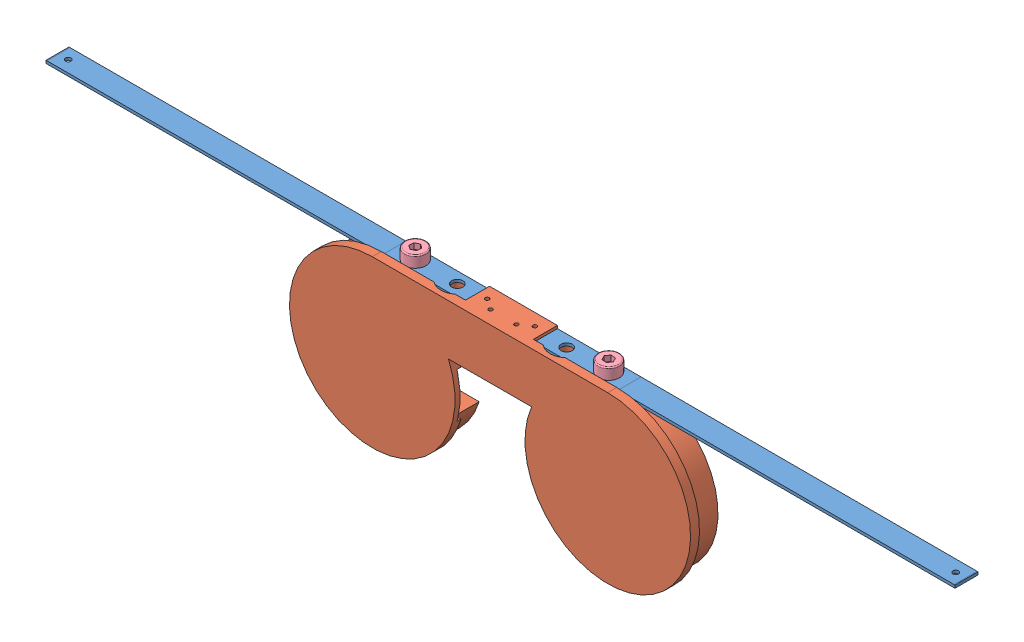
SolidWorks assembly dedede, configuration Valor predeterminado. Lengths in mm.
Overall size (162.11 31.03 6.53).
11 component instances, 4 part files, 31 mates.
Components (placement in the parent):
- antena_01-1: antena_01 [da] at origin size (75 0.58 4.1)
- base deploy^dedede-1: base deploy^dedede [Valor predeterminado] at (-0.0901 0.0537 3.449) x (1 0.000002 0) z (0 0 1) size (71.53 29.53 5.9) (virtual)
- antena_01-3: antena_01 [da] at (-176.7223 -0.0003 10.598) x (-1 -0.000004 0) z (0 0 -1) size (75 0.58 4.1)
- hex thin nut chamfered gradeab_din-5: hex thin nut chamfered gradeab_din [Hexagon Thin Nut ISO 4035 - M2 - N] at (-71.0809 -2.7192 5.3304) x (1 0.000002 0) z (-0.000002 1 0) size (4 4.62 1.2)
- hex thin nut chamfered gradeab_din-6: hex thin nut chamfered gradeab_din [Hexagon Thin Nut ISO 4035 - M2 - N] at (-78.5809 -2.7192 5.3304) x (1 0.000002 0) z (-0.000002 1 0) size (4 4.62 1.2)
- hex thin nut chamfered gradeab_din-7: hex thin nut chamfered gradeab_din [Hexagon Thin Nut ISO 4035 - M2 - N] at (-98.1414 -2.7192 5.2676) x (1 0.000002 0) z (-0.000002 1 0) size (4 4.62 1.2)
- hex thin nut chamfered gradeab_din-8: hex thin nut chamfered gradeab_din [Hexagon Thin Nut ISO 4035 - M2 - N] at (-105.6414 -2.7192 5.2676) x (1 0.000002 0) z (-0.000002 1 0) size (4 4.62 1.2)
- socket head cap screw 4762_din-2: socket head cap screw 4762_din [EN ISO 4762 M2 x 6 - 6N] at (-71.0809 2.5 5.3304) x (0.000002 -1 0) z (-0.074317 0 0.997235) size (8 3.8 3.8)
- socket head cap screw 4762_din-4: socket head cap screw 4762_din [EN ISO 4762 M2 x 6 - 6N] at (-105.6414 2.4999 5.2676) x (0.000002 -1 0) z (-0.570733 -0.000001 0.821136) size (8 3.8 3.8)
- hex thin nut chamfered gradeab_din-9: hex thin nut chamfered gradeab_din [Hexagon Thin Nut ISO 4035 - M5 - N] at (-109.4341 -13.763 7.149) x (0.866026 -0.499998 0) z (0 0 1) size (8 9.24 2.7)
- hex thin nut chamfered gradeab_din-10: hex thin nut chamfered gradeab_din [Hexagon Thin Nut ISO 4035 - M5 - N] at (-67.4341 -13.7629 7.149) x (0.866026 -0.499998 0) z (0 0 1) size (8 9.24 2.7)
Mates (geometry in assembly coordinates):
- Coincidente4: coincident aligned: plane of antena_01-1 through (0 0 0) normal (0 0 1)
- Coincidente5: coincident aligned: plane of antena_01-1 through (0 0 0) normal (0 1 0)
- Coincidente6: coincident aligned: plane of antena_01-1 through (0 0 0) normal (1 0 0)
- Coincidente13: coincident anti-aligned: plane of Peça6^dedede-1 through (-0.0901 0.0001 3.249) normal (-0.000002 1 0); plane of antena_01-3 through (-176.7223 -0.0002 10.598) normal (0.000002 -1 0)
- Coincidente14: coincident aligned: plane of base deploy^dedede-1 through (-0.0901 0.0537 3.249) normal (0 0 -1); plane of antena_01-3 through (-94.4139 0.5783 3.249) normal (0 0 -1)
- Coincidente15: coincident aligned: plane of antena_01-1 through (-7.3085 0.4475 3.249) normal (0 0 -1); plane of base deploy^dedede-1 through (-0.0901 0.0537 3.249) normal (0 0 -1)
- Coincidente16: coincident anti-aligned: plane of antena_01-1 through (0 0.0001 0) normal (0.000002 -1 0); plane of Peça6^dedede-1 through (-0.0901 0.0001 3.249) normal (-0.000002 1 0)
- Coincidente27: coincident anti-aligned: plane of antena_01-1 through (-82.3089 0.5 3.249) normal (-1 -0.000002 0); plane of base deploy^dedede-1 through (-82.3089 1 8.449) normal (1 0.000002 0)
- Coincidente28: coincident anti-aligned: plane of base deploy^dedede-1 through (-94.4134 1 3.249) normal (-1 -0.000002 0); plane of antena_01-3 through (-94.4134 0.5 7.349) normal (1 0.000002 0)
- Coincidente37: coincident anti-aligned: plane of base deploy^dedede-1 through (-69.0809 -4.3191 8.949) normal (-1 -0.000002 0); plane of hex thin nut chamfered gradeab_din-5 through (-69.0809 -3.9191 4.1757) normal (1 0.000002 0)
- Coincidente39: coincident anti-aligned: plane of base deploy^dedede-1 through (-69.0809 -2.7191 8.949) normal (0.000002 -1 0); plane of hex thin nut chamfered gradeab_din-5 through (-71.0809 -2.7192 3.021) normal (-0.000002 1 0)
- Coincidente40: coincident anti-aligned: plane of base deploy^dedede-1 through (-76.5814 -4.3192 8.949) normal (-1 -0.000002 0); plane of hex thin nut chamfered gradeab_din-6 through (-76.5809 -3.9192 4.1757) normal (1 0.000002 0)
- Coincidente41: coincident anti-aligned: plane of base deploy^dedede-1 through (-80.5814 -2.7192 8.949) normal (0.000002 -1 0); plane of hex thin nut chamfered gradeab_din-6 through (-78.5809 -2.7192 3.021) normal (-0.000002 1 0)
- Concêntrico12: concentric anti-aligned: circle of base deploy^dedede-1; circle of hex thin nut chamfered gradeab_din-6
- Coincidente42: coincident anti-aligned: plane of base deploy^dedede-1 through (-100.1408 -2.7192 8.949) normal (0.000002 -1 0); plane of hex thin nut chamfered gradeab_din-7 through (-98.1414 -2.7192 2.9582) normal (-0.000002 1 0)
- Coincidente43: coincident anti-aligned: plane of base deploy^dedede-1 through (-96.1408 -4.3192 8.949) normal (-1 -0.000002 0); plane of hex thin nut chamfered gradeab_din-7 through (-96.1414 -3.9192 4.1129) normal (1 0.000002 0)
- Concêntrico13: concentric anti-aligned: circle of base deploy^dedede-1; circle of hex thin nut chamfered gradeab_din-7
- Coincidente44: coincident anti-aligned: plane of base deploy^dedede-1 through (-107.6414 -2.7192 8.949) normal (0.000002 -1 0); plane of hex thin nut chamfered gradeab_din-8 through (-105.6414 -2.7192 2.9582) normal (-0.000002 1 0)
- Coincidente45: coincident anti-aligned: plane of base deploy^dedede-1 through (-103.6414 -4.3192 8.949) normal (-1 -0.000002 0); plane of hex thin nut chamfered gradeab_din-8 through (-103.6414 -3.9192 4.1129) normal (1 0.000002 0)
- Concêntrico19: concentric aligned: cylinder of base deploy^dedede-1 through (-71.0809 -6 5.3304) axis (-0.000002 1 0) radius 1; cylinder of socket head cap screw 4762_din-2 through (-71.0809 34.25 5.3304) axis (-0.000002 1 0) radius 1.9
- Concêntrico21: concentric aligned: cylinder of base deploy^dedede-1 through (-105.6414 -6.0001 5.2676) axis (-0.000002 1 0) radius 1; cylinder of socket head cap screw 4762_din-4 through (-105.6415 34.2499 5.2676) axis (-0.000002 1 0) radius 1.9
- Paralelo5: parallel aligned: cylinder of hex thin nut chamfered gradeab_din-5 through (-71.0809 -3.9192 5.3304) axis (-0.000002 1 0) radius 0.8; cylinder of socket head cap screw 4762_din-2 through (-71.0809 34.25 5.3304) axis (-0.000002 1 0) radius 1
- Paralelo6: parallel aligned: cylinder of hex thin nut chamfered gradeab_din-8 through (-105.6414 -3.9192 5.2676) axis (-0.000002 1 0) radius 0.8; cylinder of socket head cap screw 4762_din-4 through (-105.6415 34.2499 5.2676) axis (-0.000002 1 0) radius 1
- Coincidente52: coincident anti-aligned: plane of antena_01-3 through (-176.7223 0.4998 10.598) normal (-0.000002 1 0); plane of socket head cap screw 4762_din-4 through (-104.0812 0.4999 6.352) normal (0.000002 -1 0)
- Coincidente53: coincident anti-aligned: plane of antena_01-1 through (0 0.5001 0) normal (-0.000002 1 0); plane of socket head cap screw 4762_din-2 through (-69.1861 0.5 5.4716) normal (0.000002 -1 0)
- Coincidente56: coincident anti-aligned: plane of base deploy^dedede-1 through (-0.09 -17.7628 8.249) normal (-0.000002 1 0); plane of hex thin nut chamfered gradeab_din-9 through (-111.7435 -17.763 4.449) normal (0.000002 -1 0)
- Concêntrico26: concentric aligned: circle of base deploy^dedede-1; circle of hex thin nut chamfered gradeab_din-9
- Coincidente58: coincident anti-aligned: plane of base deploy^dedede-1 through (-0.09 -9.7628 8.249) normal (0.000002 -1 0); plane of hex thin nut chamfered gradeab_din-10 through (-65.1247 -9.7629 4.449) normal (-0.000002 1 0)
- Concêntrico27: concentric aligned: circle of base deploy^dedede-1; circle of hex thin nut chamfered gradeab_din-10
- Coincidente59: coincident anti-aligned: plane of base deploy^dedede-1 through (-114.1341 -17.763 4.449) normal (0 0 1); plane of hex thin nut chamfered gradeab_din-9 through (-107.1247 -9.763 4.449) normal (0 0 -1)
- Coincidente60: coincident anti-aligned: plane of base deploy^dedede-1 through (-62.7341 -9.7629 4.449) normal (0 0 1); plane of hex thin nut chamfered gradeab_din-10 through (-65.1247 -9.7629 4.449) normal (0 0 -1)
